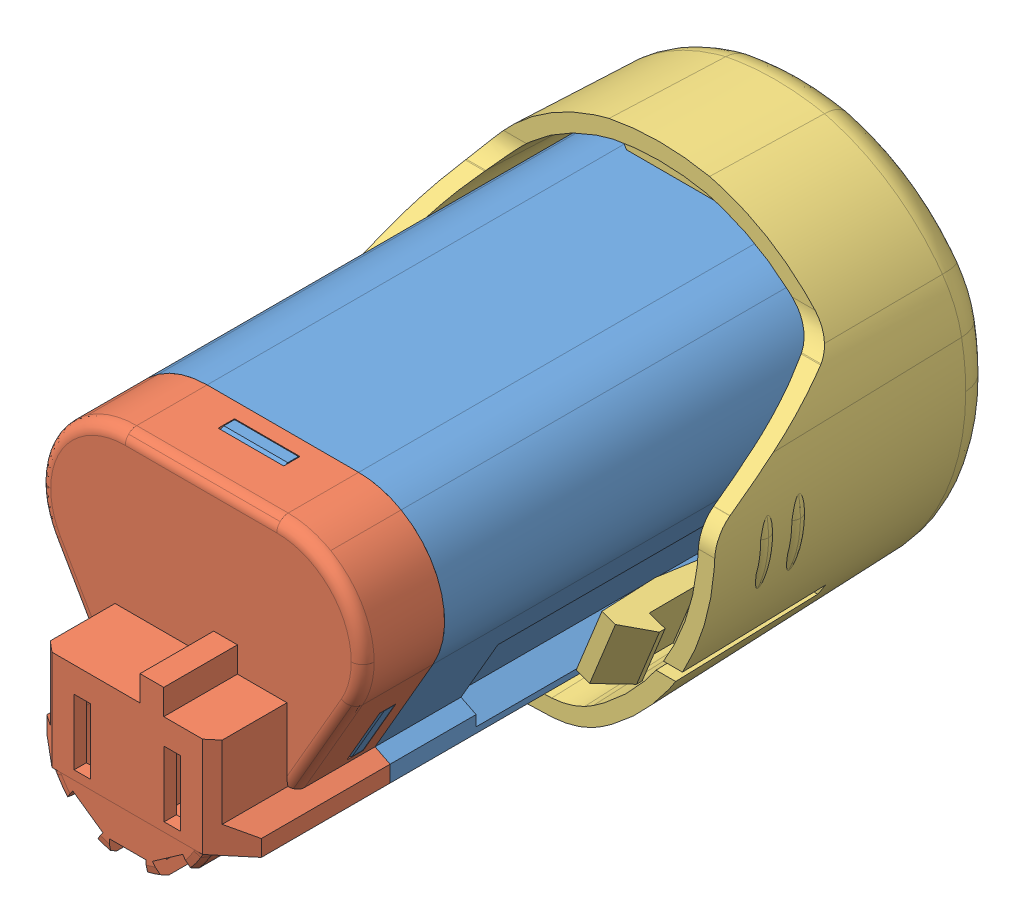
SolidWorks assembly Battery, configuration Default. Lengths in mm.
Overall size (51.94 49.97 82.98).
4 component instances, 3 part files, 0 mates.
Components (placement in the parent):
- battery.stp-1: battery.stp [Default] at origin size (51.94 49.97 82.98)
  - BOSCH_BATTERY_108_BODY.stp-1: BOSCH_BATTERY_108_BODY.stp [Default] at (1.6476 0.6188 12.9785) x (1 -0.000001 0) z (0 0 1) size (39.5 37.7 66)
  - BOSCH_BATTERY_108_TOP.stp-1: BOSCH_BATTERY_108_TOP.stp [Default] at (1.6476 0.6188 73.9785) x (1 -0.000001 0) z (0 0 1) size (39.5 37.02 19)
  - BOSCH_BATTERY_108_CAP2.stp-1: BOSCH_BATTERY_108_CAP2.stp [Default] at (1.6476 -0.3955 10) x (1 -0.000001 0) z (0 0 1) size (51.94 49.97 42.78)
